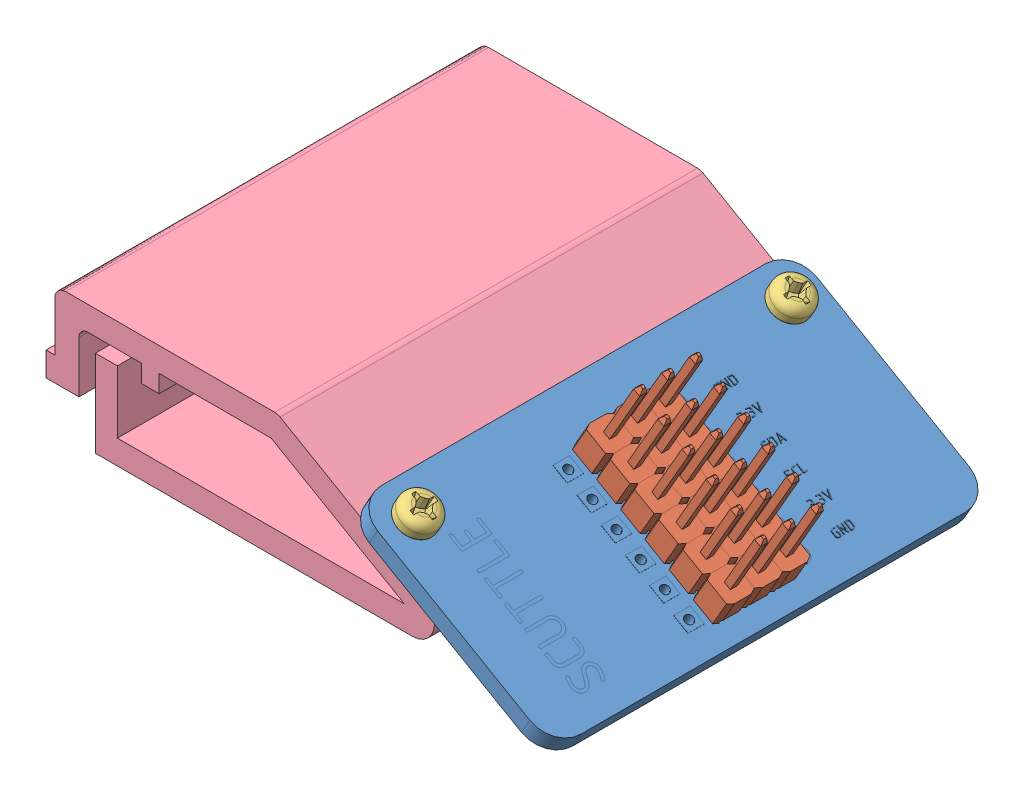
SolidWorks assembly i2c_assem, configuration Default. Lengths in mm.
Overall size (51.24 23.09 40).
10 component instances, 5 part files, 6 mates.
Components (placement in the parent):
- i2C_Breakout_ASSY-1: i2C_Breakout_ASSY [Default] at (46.111 -7.05 0) x (0 0 -1) z (-0.866025 0.5 0) size (40 14.54 21)
  - circuitBoardi2c v1-1: circuitBoardi2c v1 [6x5] x (1 0 0) z (0 0 -1) size (40 1.6 21)
  - pinHeader-2: pinHeader [6 pin] at (3.81 -1.53 3.93) x (0 0 1) z (1 0 0) size (15.24 11.54 2.54)
  - pinHeader-3: pinHeader [6 pin] at (1.27 -1.53 3.93) x (0 0 1) z (1 0 0) size (15.24 11.54 2.54)
  - pinHeader-4: pinHeader [6 pin] at (-1.27 -1.53 3.93) x (0 0 1) z (1 0 0) size (15.24 11.54 2.54)
  - pinHeaderBend-1: pinHeaderBend [6 pin] at (-5.08 -1.53 5.2) x (0 0 1) z (1 0 0) size (15.24 7.32 8.52)
  - pinHeaderBend-2: pinHeaderBend [6 pin] at (5.08 -1.53 -7.5) x (0 0 -1) z (-1 0 0) size (15.24 7.32 8.52)
  - screw_m2.5_course-1: screw_m2.5_course [96817A209] at (-17 -1.53 7.5) x (-1 0 0) z (0 -1 0) size (3.35 3.35 7.64)
  - screw_m2.5_course-2: screw_m2.5_course [96817A209] at (17 -1.53 7.5) x (-1 0 0) z (0 -1 0) size (3.35 3.35 7.64)
- i2cBracket_v3-1: i2cBracket_v3 [Default] at origin size (35.37 11.4 38.5)
Mates (geometry in assembly coordinates):
- Coincident3: coincident anti-aligned: plane of i2C_Breakout_ASSY-1/circuitBoardi2c v1-1 through (46.111 -7.05 0) normal (-0.5 -0.866025 0); plane of i2cClip-1 through (30.6 1.9053 19.25) normal (0.5 0.866025 0)
- Coincident4: coincident aligned: plane of i2cClip-1 through (0 0 0) normal (0 1 0)
- Concentric1: concentric aligned: line of i2C_Breakout_ASSY-1 through (39.6158 -3.3 17) axis (0.5 0.866025 0); cylinder of i2cClip-1 through (29.4064 -20.9832 17) axis (0.5 0.866025 0) radius 0.9
- Coincident5: coincident aligned: plane of i2cClip-1 through (0 0 0) normal (0 0 1)
- Coincident7: coincident aligned: plane of i2cClip-1 through (0 0 0) normal (1 0 0)
- Coincident6: coincident anti-aligned: plane of i2C_Breakout_ASSY-1 through (46.111 -7.05 0) normal (0 0 -1)
